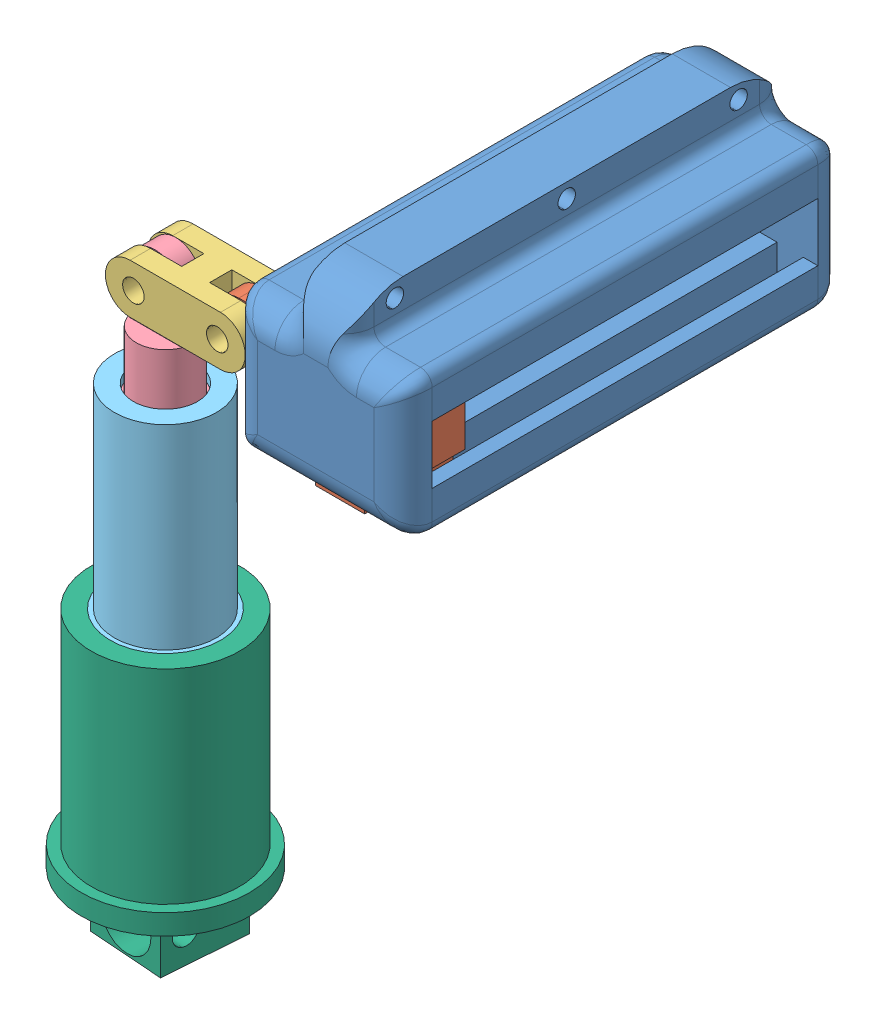
SolidWorks assembly transmission_assem_L, configuration Default. Lengths in mm.
Overall size (64.88 116.85 83.09).
7 component instances, 6 part files, 18 mates.
Components (placement in the parent):
- transmissionblockdraft1-1: transmissionblockdraft1 [Default] at (20.9703 52.1158 91.803) size (30 31 76.2)
- transmission_slider-1: transmission_slider [Default] at (20.1803 46.4453 86.803) size (37.65 24 7.2)
- slider_to_tele-1: slider_to_tele [Default] at (-18.2197 54.0158 85.203) x (0 0 -1) z (0 -1 0) size (10.8 24 8.5)
- telescopic link-1: telescopic link [Default] at (-13.4197 49.7658 81.403) size (12.5 23.75 12.5)
- 2nd_tele_part-1: 2nd_tele_part [Default] at (-13.4197 49.2658 83.203) x (-0.936212 0 0.351436) z (-0.351436 0 -0.936212) size (20.5 35 20.5)
- 3rd_tele_part-1: 3rd_tele_part [Default] at (-13.4197 46.7658 83.203) x (0.997317 0 0.0732) z (-0.0732 0 0.997317) size (28.94 48.5 28.94)
- L12_100mm-1: L12_100mm [Default] at (22.4374 15.6859 225.0341) x (0.997317 0 0.0732) z (0.0732 0 -0.997317) (suppressed, hidden)
Mates (geometry in assembly coordinates):
- Parallel3: parallel anti-aligned: plane of transmissionblockdraft1-1 through (12.9703 54.1158 -21.4302) normal (0 -1 0); plane of transmission_slider-1 through (12.1803 54.0158 79.603) normal (0 1 0)
- Parallel4: parallel anti-aligned: plane of transmissionblockdraft1-1 through (15.9703 37.1158 -21.4302) normal (1 0 0); plane of transmission_slider-1 through (15.9803 34.5158 79.603) normal (-1 0 0)
- Distance1: distance = 0.01 mm anti-aligned: plane of transmission_slider-1 through (15.9803 34.5158 79.603) normal (-1 0 0); plane of transmissionblockdraft1-1 through (15.9703 37.1158 -21.4302) normal (1 0 0)
- Distance2: distance = 0.1 mm anti-aligned: plane of transmission_slider-1 through (12.1803 54.0158 79.603) normal (0 1 0); plane of transmissionblockdraft1-1 through (12.9703 54.1158 -21.4302) normal (0 -1 0)
- LimitDistance2: limit distance = 0 mm anti-aligned: plane of transmission_slider-1 through (20.1803 46.4453 86.803) normal (0 0 1); plane of transmissionblockdraft1-1 through (20.9703 52.1158 86.803) normal (0 0 -1)
- Concentric1: concentric anti-aligned: circle of transmission_slider-1; circle of slider_to_tele-1
- Coincident10: coincident anti-aligned: plane of transmission_slider-1 through (-4.0197 54.0158 81.403) normal (0 0 -1); plane of slider_to_tele-1 through (-3.8197 45.5158 81.403) normal (0 0 1)
- Coincident11: coincident aligned: plane of transmission_slider-1 through (5.9803 54.0158 79.603) normal (0 1 0); plane of slider_to_tele-1 through (-18.2197 54.0158 85.203) normal (0 1 0)
- Coincident13: coincident anti-aligned: plane of slider_to_tele-1 through (-8.6197 45.5158 81.403) normal (0 0 1); plane of telescopic link-1 through (-13.4197 49.7658 81.403) normal (0 0 -1)
- Concentric4: concentric aligned: circle of slider_to_tele-1; circle of telescopic link-1
- Concentric5: concentric anti-aligned: circle of telescopic link-1; circle of 2nd_tele_part-1
- LimitDistance3: limit distance = 0 mm anti-aligned: plane of telescopic link-1 through (-13.4197 31.7658 83.203) normal (0 1 0); plane of 2nd_tele_part-1 through (-8.2705 31.7658 81.2701) normal (0 -1 0)
- Parallel6: parallel aligned: plane of transmissionblockdraft1-1 through (5.9703 59.1158 15.603) normal (-1 0 0); plane of telescopic link-1 through (-17.6697 41.7658 85.003) normal (-1 0 0)
- Concentric6: concentric aligned: circle of 2nd_tele_part-1; circle of 3rd_tele_part-1
- LimitDistance4: limit distance = 0 mm aligned: plane of 3rd_tele_part-1 through (-22.8633 -1.7342 82.5099) normal (0 -1 0); plane of 2nd_tele_part-1 through (-3.8235 -1.7342 79.6008) normal (0 -1 0)
- Parallel7: parallel anti-aligned: plane of transmissionblockdraft1-1 through (25.9703 68.1158 15.603) normal (0 1 0); plane of ? through (-18.9312 -49.7342 229.3334) normal (0 -1 0)
- Concentric7: concentric aligned: circle of 3rd_tele_part-1; circle of ?
- Concentric8: concentric anti-aligned: circle of 3rd_tele_part-1; circle of ?
